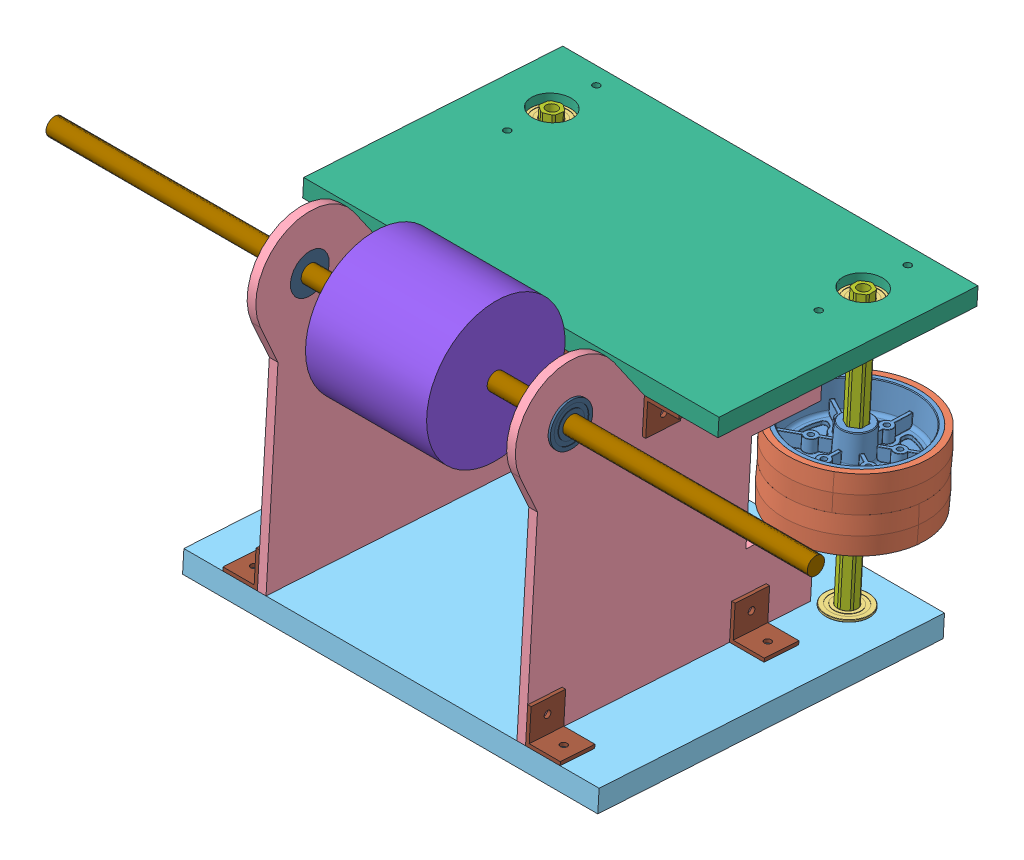
SolidWorks assembly Shooter Prototype Final, configuration Default. Lengths in mm.
Overall size (612.77 270.92 316.75).
38 component instances, 11 part files, 39 mates.
Components (placement in the parent):
- 4 in Stealth Wheel Andymark-1: 4 in Stealth Wheel Andymark [Default] at (-114.3 -102.056 -194.0122) x (0 -0.998166 0.060536) z (0.8129 0.035257 0.581335) size (25.4 101.6 101.6)
  - 4 in Stealth Wheel Andymark.STEP-1: 4 in Stealth Wheel Andymark.STEP [Default] at origin size (25.4 101.6 101.6)
    - 4in Wheel Intergreated Hub 500 HEX.STEP-1: 4in Wheel Intergreated Hub 500 HEX.STEP [Default] at origin size (25.4 92.71 92.71)
    - 4in Tread.STEP-1: 4in Tread.STEP [Default] at origin size (25.4 101.6 101.6)
- 4 in Stealth Wheel Andymark-2: 4 in Stealth Wheel Andymark [Default] at (-114.3 -124.9658 -192.6228) x (0 0.998166 -0.060536) z (-0.943026 -0.020142 -0.33211) size (25.4 101.6 101.6)
  - 4 in Stealth Wheel Andymark.STEP-1: 4 in Stealth Wheel Andymark.STEP [Default] at origin size (25.4 101.6 101.6)
    - 4in Wheel Intergreated Hub 500 HEX.STEP-1: 4in Wheel Intergreated Hub 500 HEX.STEP [Default] at origin size (25.4 92.71 92.71)
    - 4in Tread.STEP-1: 4in Tread.STEP [Default] at origin size (25.4 101.6 101.6)
- 0.5 in Thunderhex flanged bearing-2: 0.5 in Thunderhex flanged bearing [Default] at (-114.3 -204.6283 -187.8502) x (1 0 0) z (0 0.998166 -0.060536) size (31.12 31.12 7.94)
- Side wall-2: Side wall [Default] at (-92.075 -81.1536 -79.3703) x (-1 0 0) z (0 -0.060536 -0.998166) size (6.35 230.19 228.6)
- Plate 2-1: Plate 2 [Default] at (0 -212.8197 -100.0126) x (1 0 0) z (0 0.060536 0.998166) size (304.8 15.88 254)
- 0.5 in Thunderhex flanged bearing-3: 0.5 in Thunderhex flanged bearing [Default] at (-114.3 -16.0587 -199.2277) x (0.754088 -0.039759 -0.655569) z (0 -0.998166 0.060536) size (31.12 31.12 7.94)
- Plate 1-2: Plate 1 [Default] at (0 -13.1616 -112.1214) x (1 0 0) z (0 0.060536 0.998166) size (304.8 12.7 190.5)
- ThunderHex Shaft 1-1: ThunderHex Shaft 1 [Default] at (-114.3 -5.7589 -199.8524) x (-0.910826 0.024989 0.412033) z (0.41279 0.055138 0.909156) size (13.75 212.72 12.7)
- Side wall-3: Side wall [Default] at (98.425 -81.1536 -79.3703) x (-1 0 0) z (0 -0.060536 -0.998166) size (6.35 230.19 228.6)
- 0.5 in Thunderhex flanged bearing-6: 0.5 in Thunderhex flanged bearing [Default] at (114.3 -16.0587 -199.2277) x (0.754088 0.039759 0.655569) z (0 -0.998166 0.060536) size (31.12 31.12 7.94)
- ThunderHex Shaft 1-2: ThunderHex Shaft 1 [Default] at (114.3 -5.7589 -199.8524) x (-0.910826 -0.024989 -0.412033) z (-0.41279 0.055138 0.909156) size (13.75 212.72 12.7)
- 0.5 in Thunderhex flanged bearing-7: 0.5 in Thunderhex flanged bearing [Default] at (114.3 -204.6283 -187.8502) x (1 0 0) z (0 0.998166 -0.060536) size (31.12 31.12 7.94)
- 4 in Stealth Wheel Andymark-3: 4 in Stealth Wheel Andymark [Default] at (114.3 -99.6124 -194.1604) x (0 0.998166 -0.060536) z (-0.85137 0.031755 0.523603) size (25.4 101.6 101.6)
  - 4 in Stealth Wheel Andymark.STEP-1: 4 in Stealth Wheel Andymark.STEP [Default] at origin size (25.4 101.6 101.6)
    - 4in Wheel Intergreated Hub 500 HEX.STEP-1: 4in Wheel Intergreated Hub 500 HEX.STEP [Default] at origin size (25.4 92.71 92.71)
    - 4in Tread.STEP-1: 4in Tread.STEP [Default] at origin size (25.4 101.6 101.6)
- 4 in Stealth Wheel Andymark-4: 4 in Stealth Wheel Andymark [Default] at (114.3 -127.4094 -192.4746) x (0 -0.998166 0.060536) z (-0.055083 0.060444 0.996651) size (25.4 101.6 101.6)
  - 4 in Stealth Wheel Andymark.STEP-1: 4 in Stealth Wheel Andymark.STEP [Default] at origin size (25.4 101.6 101.6)
    - 4in Wheel Intergreated Hub 500 HEX.STEP-1: 4in Wheel Intergreated Hub 500 HEX.STEP [Default] at origin size (25.4 92.71 92.71)
    - 4in Tread.STEP-1: 4in Tread.STEP [Default] at origin size (25.4 101.6 101.6)
- Roller For Shooter-1: Roller For Shooter [Default] at origin size (88.9 101.6 101.6)
- _5 in shaft-1: _5 in shaft [Default] x (1 0 0) z (0 -0.760785 0.649004) size (612.77 12.7 12.7)
- _5id bearing-1: _5id bearing [Default] at (-92.075 0 0) x (0 0.65269 0.757625) z (0 -0.757625 0.65269) size (31.12 7.94 31.12)
- _5id bearing-2: _5id bearing [Default] at (92.075 0 0) x (0 0.159833 -0.987144) z (0 -0.987144 -0.159833) size (31.12 7.94 31.12)
- Polycarb mounting hardware shooter-1: Polycarb mounting hardware shooter [Default] at (-98.425 -9.7019 -55.0762) x (0 -0.998166 0.060536) z (0 -0.060536 -0.998166) size (25.4 25.4 25.4)
- Polycarb mounting hardware shooter-2: Polycarb mounting hardware shooter [Default] at (-98.425 -14.3148 -131.1364) x (0 -0.998166 0.060536) z (0 -0.060536 -0.998166) size (25.4 25.4 25.4)
- Polycarb mounting hardware shooter-8: Polycarb mounting hardware shooter [Default] at (-98.425 -199.5194 -142.9465) x (0 0.998166 -0.060536) z (0 0.060536 0.998166) size (25.4 25.4 25.4)
- Polycarb mounting hardware shooter-11: Polycarb mounting hardware shooter [Default] at (-98.425 -190.4389 6.7784) x (0 0.998166 -0.060536) z (0 0.060536 0.998166) size (25.4 25.4 25.4)
- Polycarb mounting hardware shooter-12: Polycarb mounting hardware shooter [Default] at (98.425 -197.9817 -117.5931) x (0 0.998166 -0.060536) z (0 -0.060536 -0.998166) size (25.4 25.4 25.4)
- Polycarb mounting hardware shooter-13: Polycarb mounting hardware shooter [Default] at (98.425 -15.8524 -156.4899) x (0 -0.998166 0.060536) z (0 0.060536 0.998166) size (25.4 25.4 25.4)
- Polycarb mounting hardware shooter-14: Polycarb mounting hardware shooter [Default] at (98.425 -11.2395 -80.4296) x (0 -0.998166 0.060536) z (0 0.060536 0.998166) size (25.4 25.4 25.4)
- Polycarb mounting hardware shooter-18: Polycarb mounting hardware shooter [Default] at (98.425 -188.9002 32.1505) x (0 0.998166 -0.060536) z (0 -0.060536 -0.998166) size (25.4 25.4 25.4)
Mates (geometry in assembly coordinates):
- Coincident4: coincident anti-aligned: plane of 4 in Stealth Wheel Andymark-1/4 in Stealth Wheel Andymark.STEP-1/4in Wheel Intergreated Hub 500 HEX.STEP-1 through (-89.5216 -115.6045 -227.8389) normal (0 -0.998166 0.060536); plane of 4 in Stealth Wheel Andymark-2/4 in Stealth Wheel Andymark.STEP-1/4in Wheel Intergreated Hub 500 HEX.STEP-1 through (-100.1444 -115.9397 -233.365) normal (0 0.998166 -0.060536)
- Concentric3: concentric anti-aligned: cone of 4 in Stealth Wheel Andymark-1/4 in Stealth Wheel Andymark.STEP-1/4in Tread.STEP-1 through (-114.3 -100.8342 -194.0863) axis (0 -0.998166 0.060536); cone of 4 in Stealth Wheel Andymark-2/4 in Stealth Wheel Andymark.STEP-1/4in Tread.STEP-1 through (-114.3 -126.1876 -192.5487) axis (0 0.998166 -0.060536)
- Concentric6: concentric anti-aligned: cylinder of 0.5 in Thunderhex flanged bearing-2 through (-114.3 -151.477 -191.0737) axis (0 0.998166 -0.060536) radius 14.2875; cylinder of Plate 2-1 through (-114.3 -202.2514 -187.9944) axis (0 -0.998166 0.060536) radius 14.2875
- Coincident21: coincident anti-aligned: plane of 0.5 in Thunderhex flanged bearing-2 through (-114.3 -203.1163 -202.2557) normal (0 -0.998166 0.060536); plane of Plate 2-1 through (0 -196.9738 -100.9736) normal (0 0.998166 -0.060536)
- Coincident24: coincident aligned: plane of Plate 2-1 through (-152.4 -205.0463 -234.0791) normal (-1 0 0); plane of Plate 1-2 through (-152.4 -0.4848 -112.8902) normal (-1 0 0)
- Concentric7: concentric aligned: cylinder of 0.5 in Thunderhex flanged bearing-3 through (-114.3 -69.21 -196.0043) axis (0 -0.998166 0.060536) radius 14.2875; cylinder of Plate 1-2 through (-114.3 -5.7589 -199.8524) axis (0 -0.998166 0.060536) radius 14.2748
- Parallel1: parallel anti-aligned: plane of 4 in Stealth Wheel Andymark-1/4 in Stealth Wheel Andymark.STEP-1/4in Wheel Intergreated Hub 500 HEX.STEP-1 through (-115.0209 -87.714 -187.5423) normal (0.582404 -0.04921 -0.811409); plane of ThunderHex Shaft 1-1 through (-115.8546 -217.6883 -180.2894) normal (-0.582404 0.04921 0.811409)
- Concentric9: concentric anti-aligned: circle of 4 in Stealth Wheel Andymark-1/4 in Stealth Wheel Andymark.STEP-1/4in Tread.STEP-1; circle of ThunderHex Shaft 1-1
- Coincident34: coincident anti-aligned: plane of Side wall-2 through (-98.425 -201.5867 -177.0339) normal (0 -0.998166 0.060536); plane of Plate 2-1 through (0 -196.9738 -100.9736) normal (0 0.998166 -0.060536)
- Coincident35: coincident aligned: plane of Side wall-2 through (-98.425 39.2794 18.2932) normal (0 0.060536 0.998166); plane of Plate 2-1 through (-152.4 -188.9013 32.1318) normal (0 0.060536 0.998166)
- Width3: width anti-aligned: plane of 4 in Stealth Wheel Andymark-4/4 in Stealth Wheel Andymark.STEP-1/4in Wheel Intergreated Hub 500 HEX.STEP-1 through (120.6404 -113.4897 -192.9684) normal (0 0.998166 -0.060536); plane of 4 in Stealth Wheel Andymark-3/4 in Stealth Wheel Andymark.STEP-1/4in Wheel Intergreated Hub 500 HEX.STEP-1 through (110.969 -113.8382 -198.7138) normal (0 -0.998166 0.060536); plane of Side wall-3 through (92.075 -77.9888 -184.5298) normal (0 -0.998166 0.060536); plane of Side wall-3 through (92.075 -147.7107 -180.3013) normal (0 0.998166 -0.060536)
- Width4: width anti-aligned: plane of 4 in Stealth Wheel Andymark-1/4 in Stealth Wheel Andymark.STEP-1/4in Wheel Intergreated Hub 500 HEX.STEP-1 through (-110.6017 -88.47 -200.0076) normal (0 0.998166 -0.060536); plane of 4 in Stealth Wheel Andymark-2/4 in Stealth Wheel Andymark.STEP-1/4in Wheel Intergreated Hub 500 HEX.STEP-1 through (-112.1872 -139.2268 -197.7571) normal (0 -0.998166 0.060536); plane of Side wall-2 through (-98.425 -77.9888 -184.5298) normal (0 -0.998166 0.060536); plane of Side wall-2 through (-98.425 -147.7107 -180.3013) normal (0 0.998166 -0.060536)
- Concentric14: concentric aligned: cylinder of Roller For Shooter-1 through (44.45 0 0) axis (-1 0 0) radius 6.35; cylinder of _5 in shaft-1 through (306.3875 0 0) axis (-1 0 0) radius 6.35
- Width5: width anti-aligned: plane of _5 in shaft-1 through (306.3875 0 0) normal (1 0 0); plane of Side wall-2 through (-306.3875 0 0) normal (-1 0 0); plane of _5 in shaft-1 through (-98.425 -81.1536 -79.3703) normal (-1 0 0); plane of Side wall-3 through (98.425 -81.1536 -79.3703) normal (1 0 0)
- Concentric15: concentric anti-aligned: cylinder of Side wall-2 through (-98.425 0 0) axis (1 0 0) radius 14.2875; cylinder of _5id bearing-1 through (-92.075 0 0) axis (-1 0 0) radius 14.2875
- Coincident37: coincident anti-aligned: plane of Side wall-2 through (-98.425 -81.1536 -79.3703) normal (-1 0 0); plane of _5id bearing-1 through (-98.425 10.1542 11.7868) normal (1 0 0)
- Concentric16: concentric aligned: cylinder of _5 in shaft-1 through (306.3875 0 0) axis (-1 0 0) radius 6.35; cylinder of _5id bearing-1 through (-92.075 0 0) axis (-1 0 0) radius 6.35
- Concentric17: concentric aligned: cylinder of Side wall-3 through (92.075 0 0) axis (1 0 0) radius 14.2875; cylinder of _5id bearing-2 through (92.075 0 0) axis (1 0 0) radius 14.2875
- Coincident39: coincident anti-aligned: plane of Side wall-3 through (98.425 -81.1536 -79.3703) normal (1 0 0); plane of _5id bearing-2 through (98.425 2.4866 -15.3575) normal (-1 0 0)
- Distance4: distance = 184.15 mm anti-aligned: plane of Side wall-3 through (92.075 -81.1536 -79.3703) normal (-1 0 0); plane of Side wall-2 through (-92.075 -81.1536 -79.3703) normal (1 0 0)
- Coincident43: coincident anti-aligned: plane of 0.5 in Thunderhex flanged bearing-3 through (-104.9163 -17.7834 -188.3293) normal (0 0.998166 -0.060536); plane of Plate 1-2 through (0 -13.1616 -112.1214) normal (0 -0.998166 0.060536)
- Concentric18: concentric aligned: cylinder of Plate 1-2 through (-114.3 -5.7589 -199.8524) axis (0 -0.998166 0.060536) radius 14.2748; circle of ThunderHex Shaft 1-1
- Coincident44: coincident aligned: plane of Plate 1-2 through (0 -0.4848 -112.8902) normal (0 0.998166 -0.060536); plane of ThunderHex Shaft 1-1 through (-114.3 -5.7589 -199.8524) normal (0 0.998166 -0.060536)
- Distance5: distance = 184.15 mm anti-aligned: plane of Plate 1-2 through (0 -13.1616 -112.1214) normal (0 -0.998166 0.060536); plane of Plate 2-1 through (0 -196.9738 -100.9736) normal (0 0.998166 -0.060536)
- Coincident46: coordinate: point of Roller For Shooter-1
- Width6: width anti-aligned: plane of Roller For Shooter-1 through (-44.45 0 0) normal (-1 0 0); plane of Side wall-2 through (44.45 0 0) normal (1 0 0); plane of Roller For Shooter-1 through (-92.075 -81.1536 -79.3703) normal (1 0 0); plane of Side wall-3 through (92.075 -81.1536 -79.3703) normal (-1 0 0)
- Coincident47: coincident: line of Side wall-2 through (-92.075 -9.7019 -55.0762) axis (-1 0 0); plane of Plate 1-2 through (0 2.9748 -55.845) normal (0 0.060536 0.998166)
- Concentric20: concentric aligned: cone of 4 in Stealth Wheel Andymark-3/4 in Stealth Wheel Andymark.STEP-1/4in Tread.STEP-1 through (114.3 -100.8342 -194.0863) axis (0 0.998166 -0.060536); cone of 4 in Stealth Wheel Andymark-4/4 in Stealth Wheel Andymark.STEP-1/4in Tread.STEP-1 through (114.3 -126.1876 -192.5487) axis (0 0.998166 -0.060536)
- Coincident49: coincident anti-aligned: plane of 4 in Stealth Wheel Andymark-3/4 in Stealth Wheel Andymark.STEP-1/4in Wheel Intergreated Hub 500 HEX.STEP-1 through (110.969 -113.8382 -198.7138) normal (0 -0.998166 0.060536); plane of 4 in Stealth Wheel Andymark-4/4 in Stealth Wheel Andymark.STEP-1/4in Wheel Intergreated Hub 500 HEX.STEP-1 through (120.6404 -113.4897 -192.9684) normal (0 0.998166 -0.060536)
- Concentric21: concentric anti-aligned: circle of ThunderHex Shaft 1-2; cone of 4 in Stealth Wheel Andymark-4/4 in Stealth Wheel Andymark.STEP-1/4in Tread.STEP-1 through (114.3 -126.1876 -192.5487) axis (0 0.998166 -0.060536)
- Coincident51: coincident anti-aligned: plane of Side wall-2 through (-98.425 -81.1536 -79.3703) normal (-1 0 0); plane of Polycarb mounting hardware shooter-1 through (-98.425 -11.2395 -80.4296) normal (1 0 0)
- Coincident52: coincident anti-aligned: plane of Plate 1-2 through (0 -13.1616 -112.1214) normal (0 -0.998166 0.060536); plane of Polycarb mounting hardware shooter-1 through (-98.425 -11.2395 -80.4296) normal (0 0.998166 -0.060536)
- Coincident54: coincident anti-aligned: plane of Side wall-2 through (-98.425 -81.1536 -79.3703) normal (-1 0 0); plane of Polycarb mounting hardware shooter-2 through (-98.425 -15.8524 -156.4899) normal (1 0 0)
- Coincident55: coincident anti-aligned: plane of Plate 1-2 through (0 -13.1616 -112.1214) normal (0 -0.998166 0.060536); plane of Polycarb mounting hardware shooter-2 through (-98.425 -15.8524 -156.4899) normal (0 0.998166 -0.060536)
- Distance7: distance = 76.2 mm aligned: plane of Polycarb mounting hardware shooter-2 through (-98.425 -14.3148 -131.1364) normal (0 0.060536 0.998166); plane of Plate 1-2 through (0 2.9748 -55.845) normal (0 0.060536 0.998166)
- Coincident69: coincident anti-aligned: plane of Plate 2-1 through (0 -196.9738 -100.9736) normal (0 0.998166 -0.060536); plane of Polycarb mounting hardware shooter-8 through (-98.425 -197.9817 -117.5931) normal (0 -0.998166 0.060536)
- Coincident71: coincident anti-aligned: plane of Side wall-2 through (-98.425 -81.1536 -79.3703) normal (-1 0 0); plane of Polycarb mounting hardware shooter-8 through (-98.425 -197.9817 -117.5931) normal (1 0 0)
- Coincident72: coincident aligned: plane of Plate 2-1 through (-152.4 -188.9013 32.1318) normal (0 0.060536 0.998166); plane of Polycarb mounting hardware shooter-11 through (-98.425 -188.9013 32.1318) normal (0 0.060536 0.998166)
- Coincident75: coincident aligned: plane of Plate 1-2 through (0 2.9748 -55.845) normal (0 0.060536 0.998166); plane of Polycarb mounting hardware shooter-1 through (-98.425 -9.7019 -55.0762) normal (0 0.060536 0.998166)
